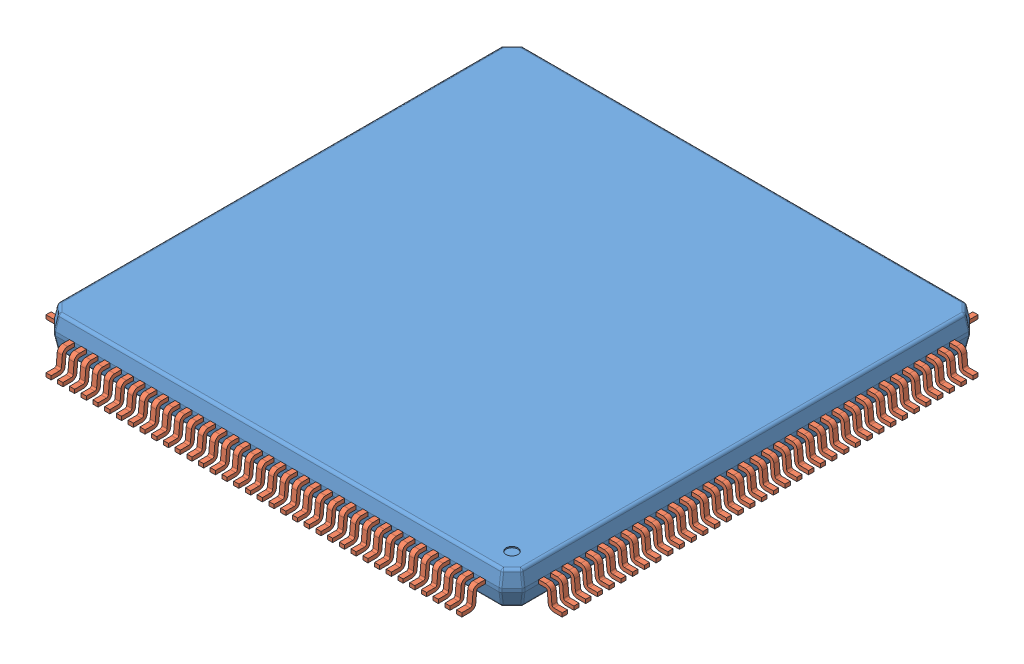
SolidWorks assembly PGE0144A, configuration Default. Lengths in mm.
Overall size (22 1.54 22).
145 component instances, 2 part files, 0 mates.
Components (placement in the parent):
- BODY_VNG144A-1: BODY_VNG144A [Default] at (0 0.16 0) x (0 0 -1) z (1 0 0) size (20 1.46 20)
- LEAD_VNG144A-1: LEAD_VNG144A [Default] at (-8.75 -0.475 10.4) size (0.22 0.89 1)
- LEAD_VNG144A-2: LEAD_VNG144A [Default] at (-8.25 -0.475 10.4) size (0.22 0.89 1)
- LEAD_VNG144A-3: LEAD_VNG144A [Default] at (-7.75 -0.475 10.4) size (0.22 0.89 1)
- LEAD_VNG144A-4: LEAD_VNG144A [Default] at (-7.25 -0.475 10.4) size (0.22 0.89 1)
- LEAD_VNG144A-5: LEAD_VNG144A [Default] at (-6.75 -0.475 10.4) size (0.22 0.89 1)
- LEAD_VNG144A-6: LEAD_VNG144A [Default] at (-6.25 -0.475 10.4) size (0.22 0.89 1)
- LEAD_VNG144A-7: LEAD_VNG144A [Default] at (-5.75 -0.475 10.4) size (0.22 0.89 1)
- LEAD_VNG144A-8: LEAD_VNG144A [Default] at (-5.25 -0.475 10.4) size (0.22 0.89 1)
- LEAD_VNG144A-9: LEAD_VNG144A [Default] at (-4.75 -0.475 10.4) size (0.22 0.89 1)
- LEAD_VNG144A-10: LEAD_VNG144A [Default] at (-4.25 -0.475 10.4) size (0.22 0.89 1)
- LEAD_VNG144A-11: LEAD_VNG144A [Default] at (-3.75 -0.475 10.4) size (0.22 0.89 1)
- LEAD_VNG144A-12: LEAD_VNG144A [Default] at (-3.25 -0.475 10.4) size (0.22 0.89 1)
- LEAD_VNG144A-13: LEAD_VNG144A [Default] at (-2.75 -0.475 10.4) size (0.22 0.89 1)
- LEAD_VNG144A-14: LEAD_VNG144A [Default] at (-2.25 -0.475 10.4) size (0.22 0.89 1)
- LEAD_VNG144A-15: LEAD_VNG144A [Default] at (-1.75 -0.475 10.4) size (0.22 0.89 1)
- LEAD_VNG144A-16: LEAD_VNG144A [Default] at (-1.25 -0.475 10.4) size (0.22 0.89 1)
- LEAD_VNG144A-17: LEAD_VNG144A [Default] at (-0.75 -0.475 10.4) size (0.22 0.89 1)
- LEAD_VNG144A-18: LEAD_VNG144A [Default] at (-0.25 -0.475 10.4) size (0.22 0.89 1)
- LEAD_VNG144A-19: LEAD_VNG144A [Default] at (0.25 -0.475 10.4) size (0.22 0.89 1)
- LEAD_VNG144A-20: LEAD_VNG144A [Default] at (0.75 -0.475 10.4) size (0.22 0.89 1)
- LEAD_VNG144A-21: LEAD_VNG144A [Default] at (1.25 -0.475 10.4) size (0.22 0.89 1)
- LEAD_VNG144A-22: LEAD_VNG144A [Default] at (1.75 -0.475 10.4) size (0.22 0.89 1)
- LEAD_VNG144A-23: LEAD_VNG144A [Default] at (2.25 -0.475 10.4) size (0.22 0.89 1)
- LEAD_VNG144A-24: LEAD_VNG144A [Default] at (2.75 -0.475 10.4) size (0.22 0.89 1)
- LEAD_VNG144A-25: LEAD_VNG144A [Default] at (3.25 -0.475 10.4) size (0.22 0.89 1)
- LEAD_VNG144A-26: LEAD_VNG144A [Default] at (3.75 -0.475 10.4) size (0.22 0.89 1)
- LEAD_VNG144A-27: LEAD_VNG144A [Default] at (4.25 -0.475 10.4) size (0.22 0.89 1)
- LEAD_VNG144A-28: LEAD_VNG144A [Default] at (4.75 -0.475 10.4) size (0.22 0.89 1)
- LEAD_VNG144A-29: LEAD_VNG144A [Default] at (5.25 -0.475 10.4) size (0.22 0.89 1)
- LEAD_VNG144A-30: LEAD_VNG144A [Default] at (5.75 -0.475 10.4) size (0.22 0.89 1)
- LEAD_VNG144A-31: LEAD_VNG144A [Default] at (6.25 -0.475 10.4) size (0.22 0.89 1)
- LEAD_VNG144A-32: LEAD_VNG144A [Default] at (6.75 -0.475 10.4) size (0.22 0.89 1)
- LEAD_VNG144A-33: LEAD_VNG144A [Default] at (7.25 -0.475 10.4) size (0.22 0.89 1)
- LEAD_VNG144A-34: LEAD_VNG144A [Default] at (7.75 -0.475 10.4) size (0.22 0.89 1)
- LEAD_VNG144A-35: LEAD_VNG144A [Default] at (8.25 -0.475 10.4) size (0.22 0.89 1)
- LEAD_VNG144A-36: LEAD_VNG144A [Default] at (8.75 -0.475 10.4) size (0.22 0.89 1)
- LEAD_VNG144A-37: LEAD_VNG144A [Default] at (10.4 -0.475 8.75) x (0 0 -1) z (1 0 0) size (0.22 0.89 1)
- LEAD_VNG144A-38: LEAD_VNG144A [Default] at (10.4 -0.475 8.25) x (0 0 -1) z (1 0 0) size (0.22 0.89 1)
- LEAD_VNG144A-39: LEAD_VNG144A [Default] at (10.4 -0.475 7.75) x (0 0 -1) z (1 0 0) size (0.22 0.89 1)
- LEAD_VNG144A-40: LEAD_VNG144A [Default] at (10.4 -0.475 7.25) x (0 0 -1) z (1 0 0) size (0.22 0.89 1)
- LEAD_VNG144A-41: LEAD_VNG144A [Default] at (10.4 -0.475 6.75) x (0 0 -1) z (1 0 0) size (0.22 0.89 1)
- LEAD_VNG144A-42: LEAD_VNG144A [Default] at (10.4 -0.475 6.25) x (0 0 -1) z (1 0 0) size (0.22 0.89 1)
- LEAD_VNG144A-43: LEAD_VNG144A [Default] at (10.4 -0.475 5.75) x (0 0 -1) z (1 0 0) size (0.22 0.89 1)
- LEAD_VNG144A-44: LEAD_VNG144A [Default] at (10.4 -0.475 5.25) x (0 0 -1) z (1 0 0) size (0.22 0.89 1)
- LEAD_VNG144A-45: LEAD_VNG144A [Default] at (10.4 -0.475 4.75) x (0 0 -1) z (1 0 0) size (0.22 0.89 1)
- LEAD_VNG144A-46: LEAD_VNG144A [Default] at (10.4 -0.475 4.25) x (0 0 -1) z (1 0 0) size (0.22 0.89 1)
- LEAD_VNG144A-47: LEAD_VNG144A [Default] at (10.4 -0.475 3.75) x (0 0 -1) z (1 0 0) size (0.22 0.89 1)
- LEAD_VNG144A-48: LEAD_VNG144A [Default] at (10.4 -0.475 3.25) x (0 0 -1) z (1 0 0) size (0.22 0.89 1)
- LEAD_VNG144A-49: LEAD_VNG144A [Default] at (10.4 -0.475 2.75) x (0 0 -1) z (1 0 0) size (0.22 0.89 1)
- LEAD_VNG144A-50: LEAD_VNG144A [Default] at (10.4 -0.475 2.25) x (0 0 -1) z (1 0 0) size (0.22 0.89 1)
- LEAD_VNG144A-51: LEAD_VNG144A [Default] at (10.4 -0.475 1.75) x (0 0 -1) z (1 0 0) size (0.22 0.89 1)
- LEAD_VNG144A-52: LEAD_VNG144A [Default] at (10.4 -0.475 1.25) x (0 0 -1) z (1 0 0) size (0.22 0.89 1)
- LEAD_VNG144A-53: LEAD_VNG144A [Default] at (10.4 -0.475 0.75) x (0 0 -1) z (1 0 0) size (0.22 0.89 1)
- LEAD_VNG144A-54: LEAD_VNG144A [Default] at (10.4 -0.475 0.25) x (0 0 -1) z (1 0 0) size (0.22 0.89 1)
- LEAD_VNG144A-55: LEAD_VNG144A [Default] at (10.4 -0.475 -0.25) x (0 0 -1) z (1 0 0) size (0.22 0.89 1)
- LEAD_VNG144A-56: LEAD_VNG144A [Default] at (10.4 -0.475 -0.75) x (0 0 -1) z (1 0 0) size (0.22 0.89 1)
- LEAD_VNG144A-57: LEAD_VNG144A [Default] at (10.4 -0.475 -1.25) x (0 0 -1) z (1 0 0) size (0.22 0.89 1)
- LEAD_VNG144A-58: LEAD_VNG144A [Default] at (10.4 -0.475 -1.75) x (0 0 -1) z (1 0 0) size (0.22 0.89 1)
- LEAD_VNG144A-59: LEAD_VNG144A [Default] at (10.4 -0.475 -2.25) x (0 0 -1) z (1 0 0) size (0.22 0.89 1)
- LEAD_VNG144A-60: LEAD_VNG144A [Default] at (10.4 -0.475 -2.75) x (0 0 -1) z (1 0 0) size (0.22 0.89 1)
- LEAD_VNG144A-61: LEAD_VNG144A [Default] at (10.4 -0.475 -3.25) x (0 0 -1) z (1 0 0) size (0.22 0.89 1)
- LEAD_VNG144A-62: LEAD_VNG144A [Default] at (10.4 -0.475 -3.75) x (0 0 -1) z (1 0 0) size (0.22 0.89 1)
- LEAD_VNG144A-63: LEAD_VNG144A [Default] at (10.4 -0.475 -4.25) x (0 0 -1) z (1 0 0) size (0.22 0.89 1)
- LEAD_VNG144A-64: LEAD_VNG144A [Default] at (10.4 -0.475 -4.75) x (0 0 -1) z (1 0 0) size (0.22 0.89 1)
- LEAD_VNG144A-65: LEAD_VNG144A [Default] at (10.4 -0.475 -5.25) x (0 0 -1) z (1 0 0) size (0.22 0.89 1)
- LEAD_VNG144A-66: LEAD_VNG144A [Default] at (10.4 -0.475 -5.75) x (0 0 -1) z (1 0 0) size (0.22 0.89 1)
- LEAD_VNG144A-67: LEAD_VNG144A [Default] at (10.4 -0.475 -6.25) x (0 0 -1) z (1 0 0) size (0.22 0.89 1)
- LEAD_VNG144A-68: LEAD_VNG144A [Default] at (10.4 -0.475 -6.75) x (0 0 -1) z (1 0 0) size (0.22 0.89 1)
- LEAD_VNG144A-69: LEAD_VNG144A [Default] at (10.4 -0.475 -7.25) x (0 0 -1) z (1 0 0) size (0.22 0.89 1)
- LEAD_VNG144A-70: LEAD_VNG144A [Default] at (10.4 -0.475 -7.75) x (0 0 -1) z (1 0 0) size (0.22 0.89 1)
- LEAD_VNG144A-71: LEAD_VNG144A [Default] at (10.4 -0.475 -8.25) x (0 0 -1) z (1 0 0) size (0.22 0.89 1)
- LEAD_VNG144A-72: LEAD_VNG144A [Default] at (10.4 -0.475 -8.75) x (0 0 -1) z (1 0 0) size (0.22 0.89 1)
- LEAD_VNG144A-73: LEAD_VNG144A [Default] at (8.75 -0.475 -10.4) x (-1 0 0) z (0 0 -1) size (0.22 0.89 1)
- LEAD_VNG144A-74: LEAD_VNG144A [Default] at (8.25 -0.475 -10.4) x (-1 0 0) z (0 0 -1) size (0.22 0.89 1)
- LEAD_VNG144A-75: LEAD_VNG144A [Default] at (7.75 -0.475 -10.4) x (-1 0 0) z (0 0 -1) size (0.22 0.89 1)
- LEAD_VNG144A-76: LEAD_VNG144A [Default] at (7.25 -0.475 -10.4) x (-1 0 0) z (0 0 -1) size (0.22 0.89 1)
- LEAD_VNG144A-77: LEAD_VNG144A [Default] at (6.75 -0.475 -10.4) x (-1 0 0) z (0 0 -1) size (0.22 0.89 1)
- LEAD_VNG144A-78: LEAD_VNG144A [Default] at (6.25 -0.475 -10.4) x (-1 0 0) z (0 0 -1) size (0.22 0.89 1)
- LEAD_VNG144A-79: LEAD_VNG144A [Default] at (5.75 -0.475 -10.4) x (-1 0 0) z (0 0 -1) size (0.22 0.89 1)
- LEAD_VNG144A-80: LEAD_VNG144A [Default] at (5.25 -0.475 -10.4) x (-1 0 0) z (0 0 -1) size (0.22 0.89 1)
- LEAD_VNG144A-81: LEAD_VNG144A [Default] at (4.75 -0.475 -10.4) x (-1 0 0) z (0 0 -1) size (0.22 0.89 1)
- LEAD_VNG144A-82: LEAD_VNG144A [Default] at (4.25 -0.475 -10.4) x (-1 0 0) z (0 0 -1) size (0.22 0.89 1)
- LEAD_VNG144A-83: LEAD_VNG144A [Default] at (3.75 -0.475 -10.4) x (-1 0 0) z (0 0 -1) size (0.22 0.89 1)
- LEAD_VNG144A-84: LEAD_VNG144A [Default] at (3.25 -0.475 -10.4) x (-1 0 0) z (0 0 -1) size (0.22 0.89 1)
- LEAD_VNG144A-85: LEAD_VNG144A [Default] at (2.75 -0.475 -10.4) x (-1 0 0) z (0 0 -1) size (0.22 0.89 1)
- LEAD_VNG144A-86: LEAD_VNG144A [Default] at (2.25 -0.475 -10.4) x (-1 0 0) z (0 0 -1) size (0.22 0.89 1)
- LEAD_VNG144A-87: LEAD_VNG144A [Default] at (1.75 -0.475 -10.4) x (-1 0 0) z (0 0 -1) size (0.22 0.89 1)
- LEAD_VNG144A-88: LEAD_VNG144A [Default] at (1.25 -0.475 -10.4) x (-1 0 0) z (0 0 -1) size (0.22 0.89 1)
- LEAD_VNG144A-89: LEAD_VNG144A [Default] at (0.75 -0.475 -10.4) x (-1 0 0) z (0 0 -1) size (0.22 0.89 1)
- LEAD_VNG144A-90: LEAD_VNG144A [Default] at (0.25 -0.475 -10.4) x (-1 0 0) z (0 0 -1) size (0.22 0.89 1)
- LEAD_VNG144A-91: LEAD_VNG144A [Default] at (-0.25 -0.475 -10.4) x (-1 0 0) z (0 0 -1) size (0.22 0.89 1)
- LEAD_VNG144A-92: LEAD_VNG144A [Default] at (-0.75 -0.475 -10.4) x (-1 0 0) z (0 0 -1) size (0.22 0.89 1)
- LEAD_VNG144A-93: LEAD_VNG144A [Default] at (-1.25 -0.475 -10.4) x (-1 0 0) z (0 0 -1) size (0.22 0.89 1)
- LEAD_VNG144A-94: LEAD_VNG144A [Default] at (-1.75 -0.475 -10.4) x (-1 0 0) z (0 0 -1) size (0.22 0.89 1)
- LEAD_VNG144A-95: LEAD_VNG144A [Default] at (-2.25 -0.475 -10.4) x (-1 0 0) z (0 0 -1) size (0.22 0.89 1)
- LEAD_VNG144A-96: LEAD_VNG144A [Default] at (-2.75 -0.475 -10.4) x (-1 0 0) z (0 0 -1) size (0.22 0.89 1)
- LEAD_VNG144A-97: LEAD_VNG144A [Default] at (-3.25 -0.475 -10.4) x (-1 0 0) z (0 0 -1) size (0.22 0.89 1)
- LEAD_VNG144A-98: LEAD_VNG144A [Default] at (-3.75 -0.475 -10.4) x (-1 0 0) z (0 0 -1) size (0.22 0.89 1)
- LEAD_VNG144A-99: LEAD_VNG144A [Default] at (-4.25 -0.475 -10.4) x (-1 0 0) z (0 0 -1) size (0.22 0.89 1)
- LEAD_VNG144A-100: LEAD_VNG144A [Default] at (-4.75 -0.475 -10.4) x (-1 0 0) z (0 0 -1) size (0.22 0.89 1)
- LEAD_VNG144A-101: LEAD_VNG144A [Default] at (-5.25 -0.475 -10.4) x (-1 0 0) z (0 0 -1) size (0.22 0.89 1)
- LEAD_VNG144A-102: LEAD_VNG144A [Default] at (-5.75 -0.475 -10.4) x (-1 0 0) z (0 0 -1) size (0.22 0.89 1)
- LEAD_VNG144A-103: LEAD_VNG144A [Default] at (-6.25 -0.475 -10.4) x (-1 0 0) z (0 0 -1) size (0.22 0.89 1)
- LEAD_VNG144A-104: LEAD_VNG144A [Default] at (-6.75 -0.475 -10.4) x (-1 0 0) z (0 0 -1) size (0.22 0.89 1)
- LEAD_VNG144A-105: LEAD_VNG144A [Default] at (-7.25 -0.475 -10.4) x (-1 0 0) z (0 0 -1) size (0.22 0.89 1)
- LEAD_VNG144A-106: LEAD_VNG144A [Default] at (-7.75 -0.475 -10.4) x (-1 0 0) z (0 0 -1) size (0.22 0.89 1)
- LEAD_VNG144A-107: LEAD_VNG144A [Default] at (-8.25 -0.475 -10.4) x (-1 0 0) z (0 0 -1) size (0.22 0.89 1)
- LEAD_VNG144A-108: LEAD_VNG144A [Default] at (-8.75 -0.475 -10.4) x (-1 0 0) z (0 0 -1) size (0.22 0.89 1)
- LEAD_VNG144A-109: LEAD_VNG144A [Default] at (-10.4 -0.475 -8.75) x (0 0 1) z (-1 0 0) size (0.22 0.89 1)
- LEAD_VNG144A-110: LEAD_VNG144A [Default] at (-10.4 -0.475 -8.25) x (0 0 1) z (-1 0 0) size (0.22 0.89 1)
- LEAD_VNG144A-111: LEAD_VNG144A [Default] at (-10.4 -0.475 -7.75) x (0 0 1) z (-1 0 0) size (0.22 0.89 1)
- LEAD_VNG144A-112: LEAD_VNG144A [Default] at (-10.4 -0.475 -7.25) x (0 0 1) z (-1 0 0) size (0.22 0.89 1)
- LEAD_VNG144A-113: LEAD_VNG144A [Default] at (-10.4 -0.475 -6.75) x (0 0 1) z (-1 0 0) size (0.22 0.89 1)
- LEAD_VNG144A-114: LEAD_VNG144A [Default] at (-10.4 -0.475 -6.25) x (0 0 1) z (-1 0 0) size (0.22 0.89 1)
- LEAD_VNG144A-115: LEAD_VNG144A [Default] at (-10.4 -0.475 -5.75) x (0 0 1) z (-1 0 0) size (0.22 0.89 1)
- LEAD_VNG144A-116: LEAD_VNG144A [Default] at (-10.4 -0.475 -5.25) x (0 0 1) z (-1 0 0) size (0.22 0.89 1)
- LEAD_VNG144A-117: LEAD_VNG144A [Default] at (-10.4 -0.475 -4.75) x (0 0 1) z (-1 0 0) size (0.22 0.89 1)
- LEAD_VNG144A-118: LEAD_VNG144A [Default] at (-10.4 -0.475 -4.25) x (0 0 1) z (-1 0 0) size (0.22 0.89 1)
- LEAD_VNG144A-119: LEAD_VNG144A [Default] at (-10.4 -0.475 -3.75) x (0 0 1) z (-1 0 0) size (0.22 0.89 1)
- LEAD_VNG144A-120: LEAD_VNG144A [Default] at (-10.4 -0.475 -3.25) x (0 0 1) z (-1 0 0) size (0.22 0.89 1)
- LEAD_VNG144A-121: LEAD_VNG144A [Default] at (-10.4 -0.475 -2.75) x (0 0 1) z (-1 0 0) size (0.22 0.89 1)
- LEAD_VNG144A-122: LEAD_VNG144A [Default] at (-10.4 -0.475 -2.25) x (0 0 1) z (-1 0 0) size (0.22 0.89 1)
- LEAD_VNG144A-123: LEAD_VNG144A [Default] at (-10.4 -0.475 -1.75) x (0 0 1) z (-1 0 0) size (0.22 0.89 1)
- LEAD_VNG144A-124: LEAD_VNG144A [Default] at (-10.4 -0.475 -1.25) x (0 0 1) z (-1 0 0) size (0.22 0.89 1)
- LEAD_VNG144A-125: LEAD_VNG144A [Default] at (-10.4 -0.475 -0.75) x (0 0 1) z (-1 0 0) size (0.22 0.89 1)
- LEAD_VNG144A-126: LEAD_VNG144A [Default] at (-10.4 -0.475 -0.25) x (0 0 1) z (-1 0 0) size (0.22 0.89 1)
- LEAD_VNG144A-127: LEAD_VNG144A [Default] at (-10.4 -0.475 0.25) x (0 0 1) z (-1 0 0) size (0.22 0.89 1)
- LEAD_VNG144A-128: LEAD_VNG144A [Default] at (-10.4 -0.475 0.75) x (0 0 1) z (-1 0 0) size (0.22 0.89 1)
- LEAD_VNG144A-129: LEAD_VNG144A [Default] at (-10.4 -0.475 1.25) x (0 0 1) z (-1 0 0) size (0.22 0.89 1)
- LEAD_VNG144A-130: LEAD_VNG144A [Default] at (-10.4 -0.475 1.75) x (0 0 1) z (-1 0 0) size (0.22 0.89 1)
- LEAD_VNG144A-131: LEAD_VNG144A [Default] at (-10.4 -0.475 2.25) x (0 0 1) z (-1 0 0) size (0.22 0.89 1)
- LEAD_VNG144A-132: LEAD_VNG144A [Default] at (-10.4 -0.475 2.75) x (0 0 1) z (-1 0 0) size (0.22 0.89 1)
- LEAD_VNG144A-133: LEAD_VNG144A [Default] at (-10.4 -0.475 3.25) x (0 0 1) z (-1 0 0) size (0.22 0.89 1)
- LEAD_VNG144A-134: LEAD_VNG144A [Default] at (-10.4 -0.475 3.75) x (0 0 1) z (-1 0 0) size (0.22 0.89 1)
- LEAD_VNG144A-135: LEAD_VNG144A [Default] at (-10.4 -0.475 4.25) x (0 0 1) z (-1 0 0) size (0.22 0.89 1)
- LEAD_VNG144A-136: LEAD_VNG144A [Default] at (-10.4 -0.475 4.75) x (0 0 1) z (-1 0 0) size (0.22 0.89 1)
- LEAD_VNG144A-137: LEAD_VNG144A [Default] at (-10.4 -0.475 5.25) x (0 0 1) z (-1 0 0) size (0.22 0.89 1)
- LEAD_VNG144A-138: LEAD_VNG144A [Default] at (-10.4 -0.475 5.75) x (0 0 1) z (-1 0 0) size (0.22 0.89 1)
- LEAD_VNG144A-139: LEAD_VNG144A [Default] at (-10.4 -0.475 6.25) x (0 0 1) z (-1 0 0) size (0.22 0.89 1)
- LEAD_VNG144A-140: LEAD_VNG144A [Default] at (-10.4 -0.475 6.75) x (0 0 1) z (-1 0 0) size (0.22 0.89 1)
- LEAD_VNG144A-141: LEAD_VNG144A [Default] at (-10.4 -0.475 7.25) x (0 0 1) z (-1 0 0) size (0.22 0.89 1)
- LEAD_VNG144A-142: LEAD_VNG144A [Default] at (-10.4 -0.475 7.75) x (0 0 1) z (-1 0 0) size (0.22 0.89 1)
- LEAD_VNG144A-143: LEAD_VNG144A [Default] at (-10.4 -0.475 8.25) x (0 0 1) z (-1 0 0) size (0.22 0.89 1)
- LEAD_VNG144A-144: LEAD_VNG144A [Default] at (-10.4 -0.475 8.75) x (0 0 1) z (-1 0 0) size (0.22 0.89 1)
